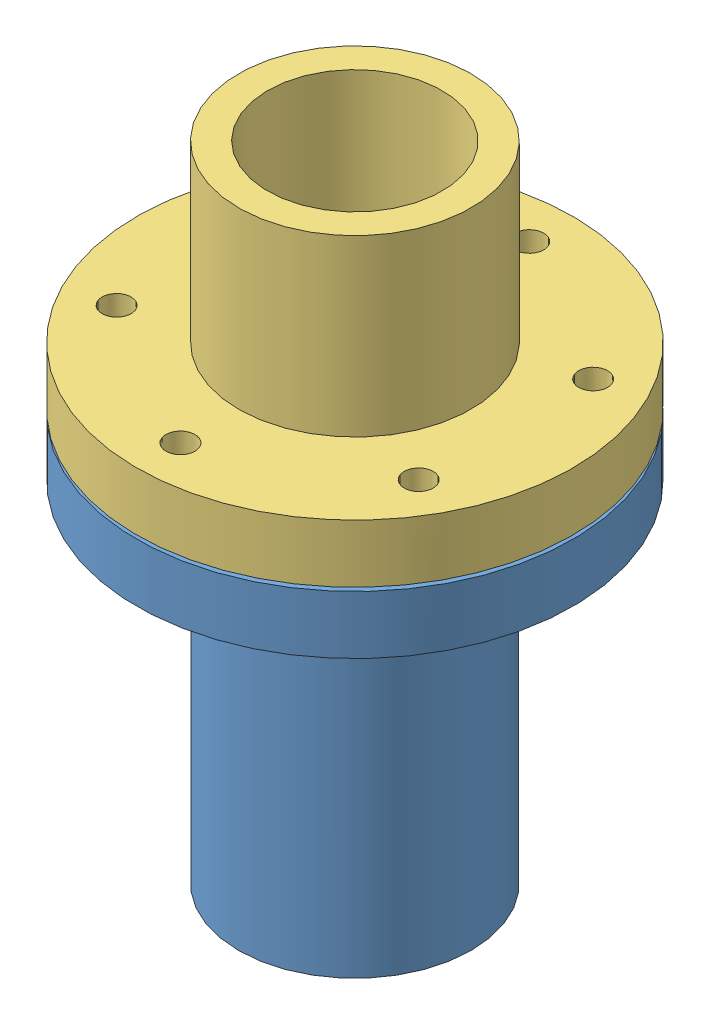
SolidWorks assembly Photoacoustic Chamber, configuration Default. Lengths in mm.
Overall size (60.94 70.25 60.94).
4 component instances, 4 part files, 7 mates.
Components (placement in the parent):
- Photoacoustic Chamber Bottom-1: Photoacoustic Chamber Bottom [Default] at (11.1535 29.7627 42.8133) size (47.62 44.45 47.62)
- Membrane-1: Membrane [Default] at (11.1535 43.0131 42.8133) x (0.993843 0 -0.110796) z (0.110796 0 0.993843) size (31.75 0.4 31.75)
- Photoacoustic Chamber Top-1: Photoacoustic Chamber Top [Default] at (2.0504 48.2894 46.0916) x (0.940852 0 -0.338819) z (0.338819 0 0.940852) size (47.62 25.4 47.62)
- Sapphire Fiber-1: Sapphire Fiber [Default] at (11.1535 4.9131 42.8133) x (-0.718309 0 0.695724) z (-0.695724 0 -0.718309) size (0.42 38.1 0.42)
Mates (geometry in assembly coordinates):
- Concentric1: concentric: cylinder of Photoacoustic Chamber Bottom-1 through (11.1535 29.7627 42.8133) axis (0 -1 0) radius 9.525; cylinder of Photoacoustic Chamber Top-1 through (11.1535 49.7599 42.8133) axis (0 1 0) radius 9.525
- Concentric2: concentric: cylinder of Photoacoustic Chamber Bottom-1 through (27.6513 36.6631 52.3383) axis (0 -1 0) radius 1.5875; cylinder of Photoacoustic Chamber Top-1 through (27.6513 49.7599 52.3383) axis (0 1 0) radius 1.5875
- Coincident1: coincident: plane of Membrane-1 through (11.1535 43.4099 42.8133) normal (0 1 0); plane of Photoacoustic Chamber Top-1 through (2.1919 43.4099 46.0406) normal (0 -1 0)
- Coincident2: coincident: plane of Photoacoustic Chamber Bottom-1 through (1.6285 43.0131 42.8133) normal (0 1 0); plane of Membrane-1 through (11.1535 43.0131 42.8133) normal (0 -1 0)
- Concentric3: concentric: cylinder of Photoacoustic Chamber Bottom-1 through (11.1535 29.7627 42.8133) axis (0 -1 0) radius 12.7; cylinder of Membrane-1 through (11.1535 43.4099 42.8133) axis (0 -1 0) radius 15.875
- Concentric4: concentric: cylinder of Photoacoustic Chamber Bottom-1 through (11.1535 29.7627 42.8133) axis (0 -1 0) radius 9.525; cylinder of Sapphire Fiber-1 through (11.1535 43.0131 42.8133) axis (0 -1 0) radius 0.2125
- Coincident3: coincident: plane of Membrane-1 through (11.1535 43.0131 42.8133) normal (0 -1 0); plane of Sapphire Fiber-1 through (11.1535 43.0131 42.8133) normal (0 1 0)
